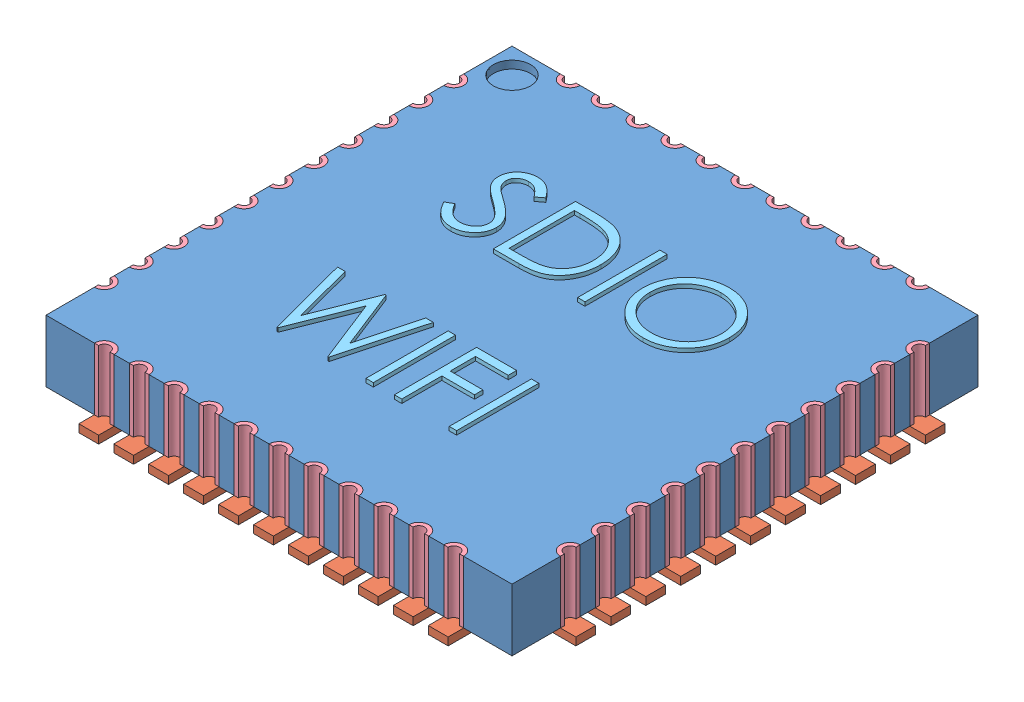
SolidWorks assembly rtl8189-board-1, configuration 默认. Lengths in mm.
Overall size (12.8 1.9 12.8).
6 component instances, 6 part files, 16 mates.
Components (placement in the parent):
- 零件1^rtl8189-board-1-1: 零件1^rtl8189-board-1 [默认] at origin size (12 1.6 12) (virtual)
- 零件2^rtl8189-board-1-1: 零件2^rtl8189-board-1 [默认] x (-1 0 0) z (0 -1 0) size (12.8 12.8 0.2) (virtual)
- 零件3^rtl8189-board-1-1: 零件3^rtl8189-board-1 [默认] x (-1 0 0) z (0 -1 0) size (2.2 2.2 0.1) (virtual)
- 零件4^rtl8189-board-1-1: 零件4^rtl8189-board-1 [默认] at origin (virtual)
- 零件5^rtl8189-board-1-1: 零件5^rtl8189-board-1 [默认] at (0 1.6 0) x (1 0 0) z (0 1 0) size (12 12 1.6) (virtual)
- 零件6^rtl8189-board-1-1: 零件6^rtl8189-board-1 [默认] at (0 1.6 0) x (1 0 0) z (0 1 0) size (6.7 6.7 0.1) (virtual)
Mates (geometry in assembly coordinates):
- 在位1: in place: plane of ? through (0 0 0) normal (0 -1 0); plane of ? through (0 0 0) normal (0 -1 0); moOrthogonalPlaneRef_w of ? through (0 0 0) normal (0 -1 0); plane of ? through (0 0 0) normal (0 0 -1); plane of ? through (0 0 0) normal (0 -1 0); plane of ? through (0 0 0) normal (-1 0 0); plane of ? through (0 0 0) normal (0 -1 0); unknown of ?
- 重合1: coincident aligned: plane of ?; plane of ?
- 重合2: coincident aligned: moOrthogonalPlaneRef_w of 零件1^装配体4-1 through (0 0 0) normal (0 0 -1); plane of 零件2^装配体4-1 through (0 0 0) normal (0 0 -1)
- 重合3: coincident anti-aligned: moOrthogonalPlaneRef_w of 零件1^装配体4-1 through (0 0 0) normal (1 0 0); plane of 零件2^装配体4-1 through (0 0 0) normal (-1 0 0)
- 在位2: in place: plane of ? through (0 0 0) normal (0 -1 0); plane of ? through (0 0 0) normal (0 -1 0); plane of ? through (0 0 0) normal (0 -1 0); plane of ? through (0 0 0) normal (0 0 -1); plane of ? through (0 0 0) normal (0 -1 0); plane of ? through (0 0 0) normal (-1 0 0); plane of ? through (0 0 0) normal (0 -1 0); unknown of ?
- 重合4: coincident aligned: plane of ?; plane of ?
- 重合5: coincident aligned: moOrthogonalPlaneRef_w of 零件1^装配体4-1 through (0 0 0) normal (0 0 -1); plane of 零件3^装配体4-1 through (0 0 0) normal (0 0 -1)
- 重合6: coincident anti-aligned: moOrthogonalPlaneRef_w of 零件1^装配体4-1 through (0 0 0) normal (1 0 0); plane of 零件3^装配体4-1 through (0 0 0) normal (-1 0 0)
- 在位3: in place: plane of ? through (0 1.6 0) normal (0 1 0); plane of ? through (0 1.6 0) normal (0 1 0); plane of ? through (0 1.6 0) normal (0 1 0); plane of ? through (0 1.6 0) normal (0 0 -1); plane of ? through (0 1.6 0) normal (0 1 0); plane of ? through (0 1.6 0) normal (1 0 0); plane of ? through (0 1.6 0) normal (0 1 0); unknown of ?
- 重合7: coincident aligned: plane of ?; plane of ?
- 重合8: coincident aligned: moOrthogonalPlaneRef_w of 零件1^rtl8189-board-1-1 through (0 1.6 0) normal (0 0 -1); plane of 零件5^rtl8189-board-1-1 through (0 1.6 0) normal (0 0 -1)
- 重合9: coincident anti-aligned: moOrthogonalPlaneRef_w of 零件1^rtl8189-board-1-1 through (0 1.6 0) normal (-1 0 0); plane of 零件5^rtl8189-board-1-1 through (0 1.6 0) normal (1 0 0)
- 在位4: in place: plane of ? through (0 1.6 0) normal (0 1 0); plane of ? through (0 1.6 0) normal (0 1 0); plane of ? through (0 1.6 0) normal (0 1 0); plane of ? through (0 1.6 0) normal (0 0 -1); plane of ? through (0 1.6 0) normal (0 1 0); plane of ? through (0 1.6 0) normal (1 0 0); plane of ? through (0 1.6 0) normal (0 1 0); unknown of ?
- 重合10: coincident aligned: plane of ?; plane of ?
- 重合11: coincident aligned: moOrthogonalPlaneRef_w of 零件1^rtl8189-board-1-1 through (0 1.6 0) normal (0 0 -1); plane of 零件6^rtl8189-board-1-1 through (0 1.6 0) normal (0 0 -1)
- 重合12: coincident anti-aligned: moOrthogonalPlaneRef_w of 零件1^rtl8189-board-1-1 through (0 1.6 0) normal (-1 0 0); plane of 零件6^rtl8189-board-1-1 through (0 1.6 0) normal (1 0 0)
